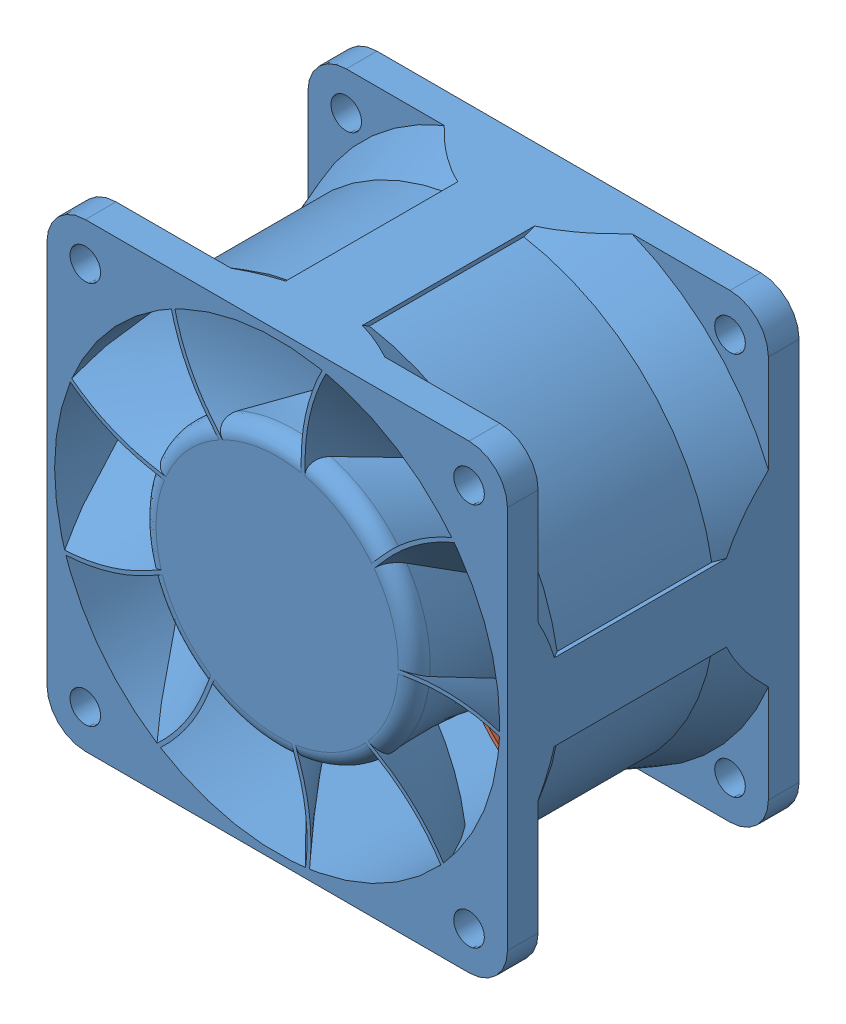
SolidWorks assembly Fan, configuration Default. Lengths in mm.
Overall size (73.23 73.27 38.35).
2 component instances, 2 part files, 2 mates.
Components (placement in the parent):
- Fan-1: Fan [Default] at (-0.0523 35.0796 35.26) size (60 60 38.16)
- Fan1-1: Fan1 [Default] at (-0.0523 35.0796 60.26) x (-0.569408 -0.822055 0) z (0.822055 -0.569408 0) size (52.72 30.19 52.56)
Mates (geometry in assembly coordinates):
- Concentric1: concentric: cylinder of assembly; cylinder of assembly; cylinder of Fan-1 through (-0.0523 35.0796 65.26) axis (0 0 -1) radius 2.5; cylinder of Fan1-1 through (-0.0523 35.0796 65.26) axis (0 0 -1) radius 2.5
- Coincident1: coincident: plane of assembly; plane of assembly; plane of Fan-1 through (-9.7883 48.3529 60.26) normal (0 0 -1); plane of Fan1-1 through (-15.0867 28.3762 60.26) normal (0 0 1)
